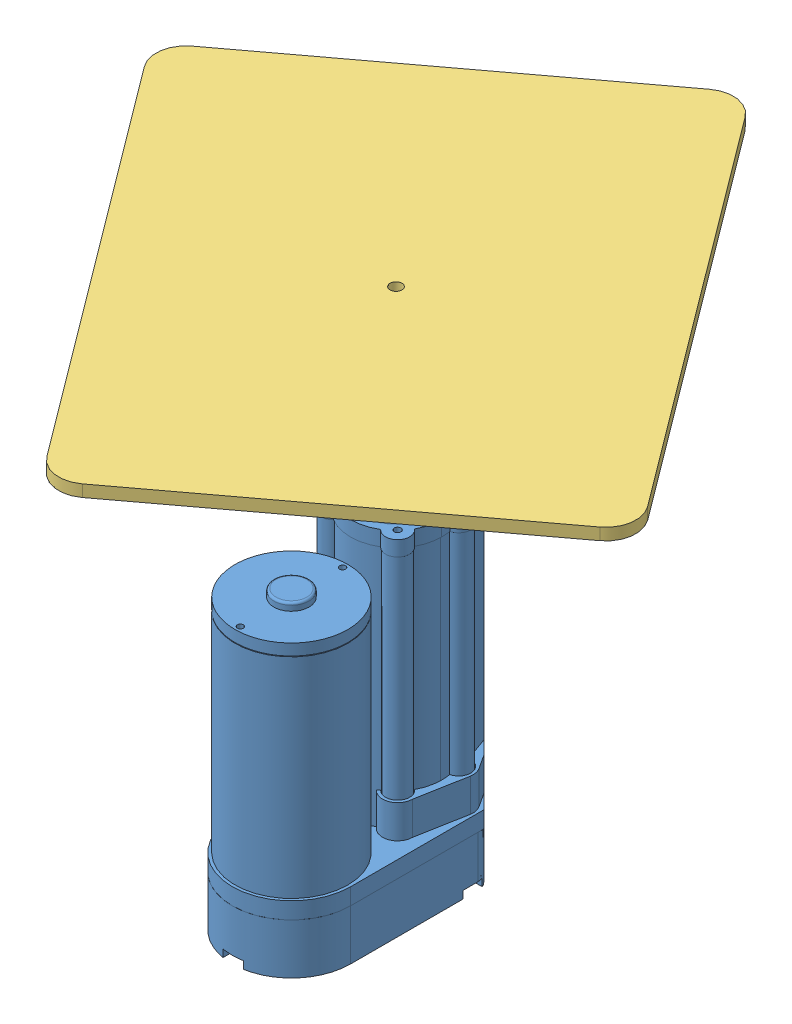
SolidWorks assembly Linear_actuator_2_inches, configuration Default. Lengths in mm.
3 component instances, 3 part files, 5 mates.
Components (placement in the parent):
- linear_actuator_2inch_stroke-1: linear_actuator_2inch_stroke [Default] at (40.005 8.509 0) x (-1 0 0) z (0 1 0) size (40 75.27 111.27)
- shaft_2inches-2: shaft_2inches [Default] at (0 86.7122 39.37) x (1 0 0) z (0 1 0) size (19.56 19.56 79.8)
- lifting mechanism - top plate-1: lifting mechanism - top plate [Default] at (20.0025 166.5106 19.685) x (-0.800924 0 0.598765) z (-0.598765 0 -0.800924) size (145 4 183)
Mates (geometry in assembly coordinates):
- Concentric1: concentric aligned: cylinder of linear_actuator_2inch_stroke-1 through (20.0025 104.919 19.685) axis (0 -1 0) radius 10.033; cylinder of shaft_2inches-2 through (20.0025 139.8006 19.685) axis (0 -1 0) radius 9.779
- Coincident13: coincident aligned: plane of shaft_2inches-2 through (0 47.2006 39.37) normal (1 0 0); plane of assembly through (0 0 0) normal (1 0 0)
- LimitDistance1: limit distance = 17 mm aligned: plane of shaft_2inches-2 through (20.0025 126.999 19.685) normal (0 1 0); plane of linear_actuator_2inch_stroke-1 through (20.0025 109.999 19.685) normal (0 1 0)
- Concentric15: concentric aligned: circle of shaft_2inches-2; circle of lifting mechanism - top plate-1
- Coincident17: coincident anti-aligned: plane of shaft_2inches-2 through (20.0025 126.999 19.685) normal (0 1 0); plane of lifting mechanism - top plate-1 through (20.0025 126.999 19.685) normal (0 -1 0)
